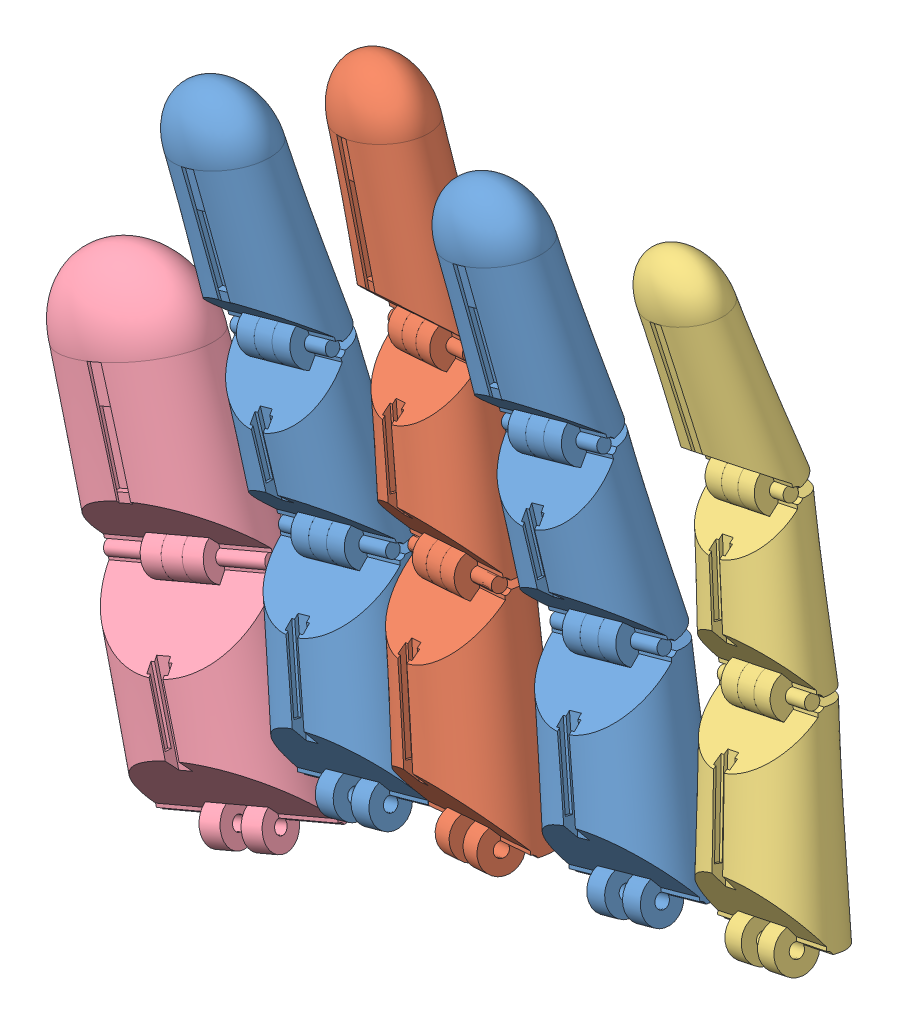
SolidWorks assembly HAND, configuration Default. Lengths in mm.
Overall size (145.65 131.44 61.16).
5 component instances, 4 part files, 0 mates.
Components (placement in the parent):
- Assem index and ring-1: Assem index and ring [Default] at (47.8917 -26.0366 65.1039) size (42.78 84.83 20.02)
- finger middle -1: finger middle  [Default] at (-8.8686 -3.8728 55.4407) x (0.625439 -0.100387 -0.773788) z (0.774295 -0.042666 0.631384) size (36.65 90.79 44.61)
- Assem pinky-1: Assem pinky [Default] at (69.8558 -5.3036 43.8779) x (0.954163 0.165406 0.249426) z (-0.221343 -0.170949 0.960096) size (27.92 81.4 26.49)
- Assem index and ring-2: Assem index and ring [Default] at (-1.5818 -42.4727 56.4653) size (42.78 84.83 20.02)
- Assem  thumb-1: Assem  thumb [Default] at (-54.4211 -18.0262 14.6768) x (0.97242 0.233079 -0.008523) z (0.027767 -0.079409 0.996455) size (31.39 70.32 23.93)
